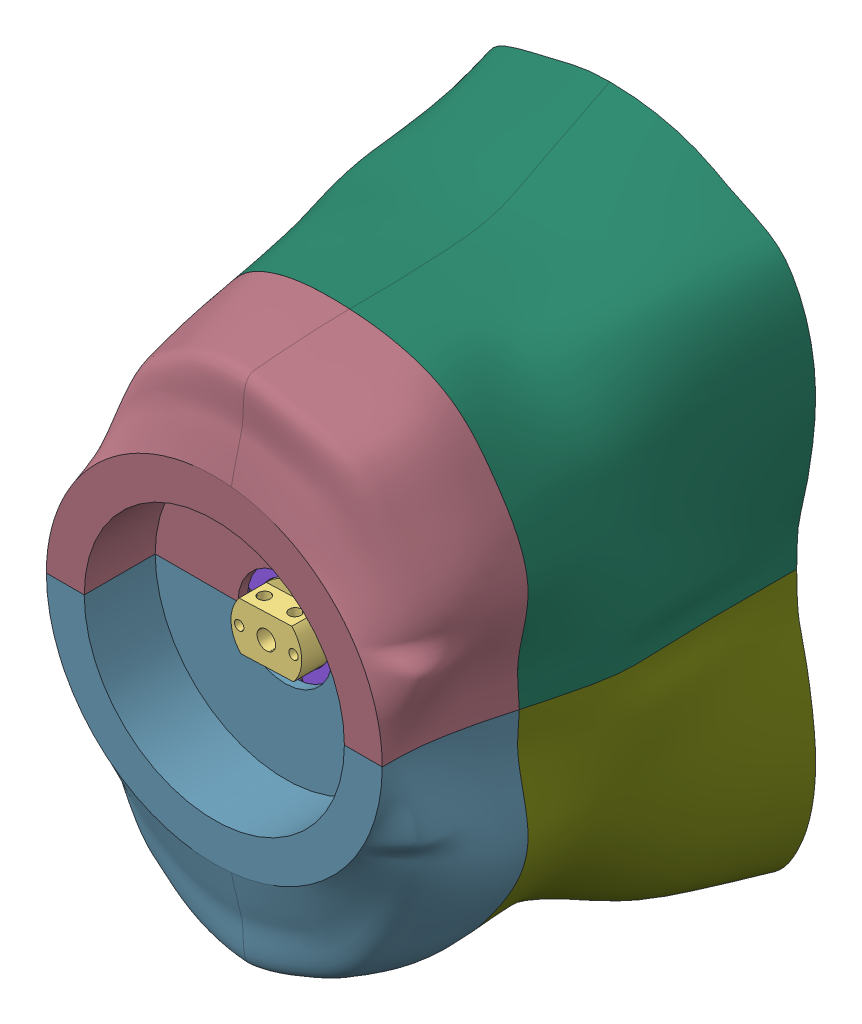
SolidWorks assembly waist top assm, configuration Default. Lengths in mm.
Overall size (177.98 294.53 170.49).
33 component instances, 16 part files, 12 mates.
Components (placement in the parent):
- gearbox-1: gearbox [Default] at (-0.6036 103.2718 100.2748) x (1 0 0) z (0 -1 0) size (88.25 74 125.51)
  - bottom housing-1: bottom housing [Default] at (7.4002 -24.2748 89.7718) x (1 0 0) z (0 1 0) size (87.5 78 20)
  - wormscrew-1: wormscrew [Default] at (21.4002 -4.2748 74.7718) x (-0.98645 0.164063 0) z (0 0 1) size (40 40 51)
  - driveshaft cog-1: driveshaft cog [Default] at (-6.5998 -9.2748 103.2718) x (-0.999334 0 0.036493) z (0 1 0) size (49.29 49.31 47)
  - top housing-1: top housing [Default] at (-6.5998 15.7252 103.2718) x (-1 0 0) z (0 -1 0) size (87.5 78 40)
  - HS-805BB-1: HS-805BB [Default] at (2.9002 10.7252 28.6693) x (1 0 0) z (0 -1 0) size (83 68.8 30)
  - 608ZZ-4: 608ZZ [Default] at (21.4002 -4.2748 120.5718) x (0.996867 0.079098 0) z (0 0 1) size (22 22 7)
  - 6806 30x42x7-1: 6806 30x42x7 [Default] at (-6.5998 -15.2748 103.2718) x (0.979879 0 0.199591) z (0 -1 0) size (42 42 7)
  - 6806 30x42x7-2: 6806 30x42x7 [Default] at (-6.5998 2.7252 103.2718) x (0.968275 0 0.249889) z (0 1 0) size (42 42 7)
  - pot holder-1: pot holder [Default] at (-6.5998 15.7252 103.2718) x (0 0 -1) z (0 1 0) size (50 60 10)
  - cog brace-1: cog brace [Default] at (18.6002 10.0252 104.6718) x (-1 0 0) z (0 -1 0) size (8.5 22.65 3)
  - pot cog-1: pot cog [Default] at (18.6002 10.0252 97.7718) x (0.754384 0 -0.656434) z (0 1 0) size (28 27.88 7.9)
  - driveshaft-1: driveshaft [Default] at (-6.5998 -9.2748 103.2718) x (0.999334 0 -0.036493) z (0 -1 0) size (36.44 35.48 27)
  - Pan Head Cross Recess Screw_ISO-22: Pan Head Cross Recess Screw_ISO [ISO 7045 - M3 x 10 - Z --- 10N] at (-26.5998 23.1252 103.2718) x (0 -1 0) z (0 0 1) size (12.35 5.6 5.6)
  - Pan Head Cross Recess Screw_ISO-23: Pan Head Cross Recess Screw_ISO [ISO 7045 - M3 x 10 - Z --- 10N] at (-6.5998 23.1252 123.2718) x (0 -1 0) z (0.495758 0 0.868461) size (12.35 5.6 5.6)
  - Pan Head Cross Recess Screw_ISO-24: Pan Head Cross Recess Screw_ISO [ISO 7045 - M3 x 10 - Z --- 10N] at (-6.5998 23.1252 83.2718) x (0 -1 0) z (0.927545 0 0.373711) size (12.35 5.6 5.6)
  - Pan Head Cross Recess Screw_ISO-3: Pan Head Cross Recess Screw_ISO [ISO 7045 - M5 x 12 - Z --- 12N] at (-34.5998 -13.2748 42.0718) x (0 0 1) z (-1 0 0) size (15.63 9.5 9.5)
  - Pan Head Cross Recess Screw_ISO-4: Pan Head Cross Recess Screw_ISO [ISO 7045 - M5 x 12 - Z --- 12N] at (-34.5998 4.7252 42.0718) x (0 0 1) z (-1 0 0) size (15.63 9.5 9.5)
  - Pan Head Cross Recess Screw_ISO-9: Pan Head Cross Recess Screw_ISO [ISO 7045 - M3 x 30 - Z --- 25N] at (36.9002 14.1252 123.7718) x (0 -1 0) z (0 0 1) size (32.35 5.6 5.6)
  - Pan Head Cross Recess Screw_ISO-13: Pan Head Cross Recess Screw_ISO [ISO 7045 - M3 x 30 - Z --- 25N] at (-18.0998 -22.6748 69.7718) x (0 1 0) z (0 0 1) size (32.35 5.6 5.6)
  - Pan Head Cross Recess Screw_ISO-14: Pan Head Cross Recess Screw_ISO [ISO 7045 - M3 x 30 - Z --- 25N] at (34.9002 14.1252 82.7718) x (0 -1 0) z (-0.981395 0 -0.191999) size (32.35 5.6 5.6)
  - Pan Head Cross Recess Screw_ISO-15: Pan Head Cross Recess Screw_ISO [ISO 7045 - M3 x 30 - Z --- 25N] at (-5.5998 14.1252 71.7718) x (0 -1 0) z (0.38373 0 0.923445) size (32.35 5.6 5.6)
  - Pan Head Cross Recess Screw_ISO-16: Pan Head Cross Recess Screw_ISO [ISO 7045 - M2 x 6 - Z --- 6N] at (18.6002 6.9252 115.2718) x (0 1 0) z (0.879308 0 -0.476254) size (7.57 4 4)
  - Pan Head Cross Recess Screw_ISO-18: Pan Head Cross Recess Screw_ISO [ISO 7045 - M3 x 5 - Z --- 5N] at (-5.9795 -13.6748 120.2605) x (0 1 0) z (-0.276322 0 0.961065) size (7.35 5.6 5.6)
  - Pan Head Cross Recess Screw_ISO-19: Pan Head Cross Recess Screw_ISO [ISO 7045 - M3 x 5 - Z --- 5N] at (7.8026 -13.6748 94.2402) x (0 1 0) z (0 0 1) size (7.35 5.6 5.6)
  - Pan Head Cross Recess Screw_ISO-20: Pan Head Cross Recess Screw_ISO [ISO 7045 - M3 x 5 - Z --- 5N] at (-21.6227 -13.6748 95.3147) x (0 1 0) z (-0.051559 0 0.99867) size (7.35 5.6 5.6)
  - Pan Head Cross Recess Screw_ISO-21: Pan Head Cross Recess Screw_ISO [ISO 7045 - M3 x 30 - Z --- 25N] at (-27.0895 14.1252 123.7718) x (0 -1 0) z (-0.304842 0 0.952403) size (32.35 5.6 5.6)
  - Pan Head Cross Recess Screw_ISO-2: Pan Head Cross Recess Screw_ISO [ISO 7045 - M5 x 12 - Z --- 12N] at (40.4002 4.7252 42.0718) x (0 0 1) z (0.747712 -0.664023 0) size (15.63 9.5 9.5)
  - Pan Head Cross Recess Screw_ISO-1: Pan Head Cross Recess Screw_ISO [ISO 7045 - M5 x 12 - Z --- 12N] at (40.4002 -13.2748 42.0718) x (0 0 1) z (0.337086 -0.941474 0) size (15.63 9.5 9.5)
- waist top lower left-1: waist top lower left [Default] at origin size (158.61 122.37 51.68)
- waist top lower right-1: waist top lower right [Default] at origin size (161.1 122.54 51.61)
- waist top upper left-1: waist top upper left [Default] at origin size (176.79 172.75 139.78)
- waist top upper right-1: waist top upper right [Default] at origin size (177.98 172.13 145.19)
Mates (geometry in assembly coordinates):
- Coincident1: coincident: point of ?; point of ?
- Coincident2: coincident: point of ?; point of ?
- Coincident3: coincident aligned: plane of ? through (-7.2035 0 126) normal (0 0 -1); plane of ? through (-7.2035 0 126) normal (0 0 -1)
- Concentric1: concentric aligned: cylinder of gearbox-1/driveshaft cog-1; circle of ?
- Coincident7: coincident: point of ?; point of ?
- Coincident8: coincident: point of ?; point of ?
- Coincident9: coincident: point of ?; point of ?
- Coincident10: coincident: point of ?; point of ?
- Coincident11: coincident: point of ?; point of ?
- Coincident12: coincident: point of ?; point of ?
- Coincident13: coincident anti-aligned: plane of gearbox-1/top housing-1 through (-2.2035 35.5 116) normal (0 0 1); plane of ? through (36.0401 -26 116) normal (0 0 -1)
- Concentric2: concentric anti-aligned: circle of gearbox-1/bottom housing-1; circle of ?
